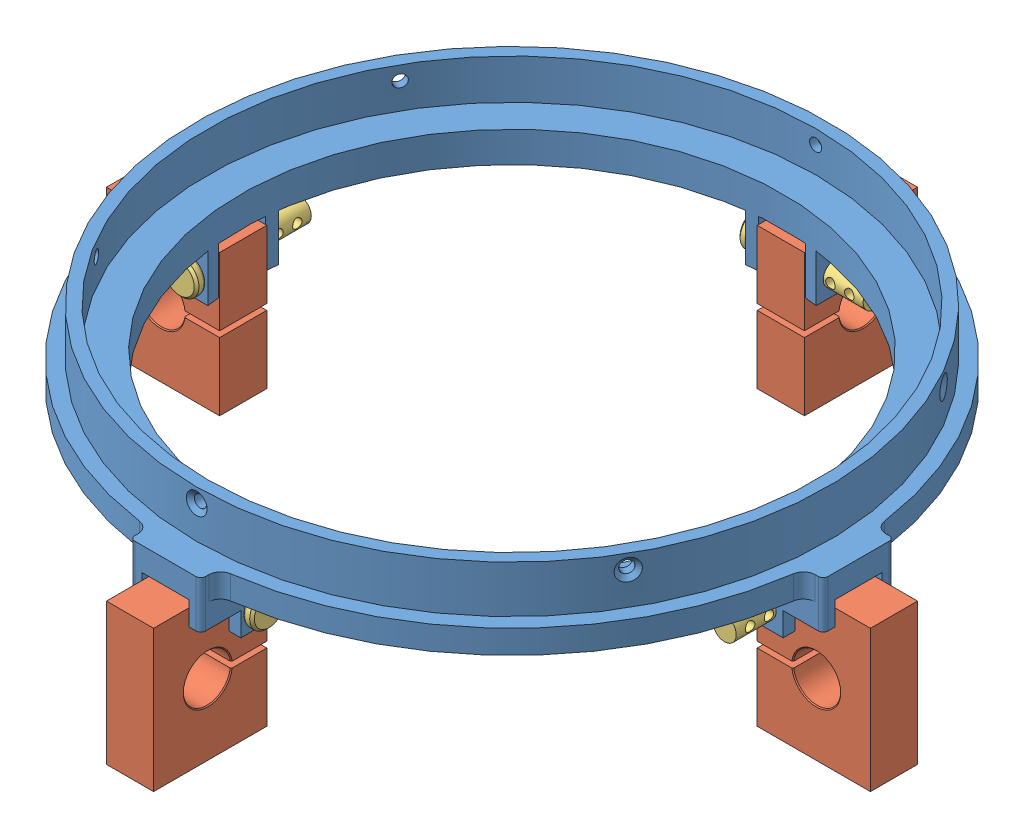
SolidWorks assembly Load cell and motor mount assembly final, configuration Default. Lengths in mm.
Overall size (205.76 59.05 205.76).
9 component instances, 3 part files, 8 mates.
Components (placement in the parent):
- Engine and Load Cell Mounting Plate3-1: Engine and Load Cell Mounting Plate3 [Default] at origin size (186.69 31.75 186.69)
- Load Cell7-4: Load Cell7 [Default] at (0 -20.955 87.6411) x (0 0 -1) z (1 0 0) size (30.48 38.1 12.7)
- load cell pin-2: load cell pin [Default] at (12.065 -7.62 77.4811) x (0 1 0) z (0 0 1) size (9.21 32.32 9.21)
- load cell pin-5: load cell pin [Default] at (77.4811 -7.62 -12.065) x (0 1 0) z (1 0 0) size (9.21 32.32 9.21)
- load cell pin-6: load cell pin [Default] at (-12.065 -7.62 -77.4811) x (0 1 0) z (0 0 -1) size (9.21 32.32 9.21)
- load cell pin-7: load cell pin [Default] at (-77.4811 -7.62 12.065) x (0 1 0) z (-1 0 0) size (9.21 32.32 9.21)
- Load Cell7-5: Load Cell7 [Default] at (87.6411 -20.955 0) x (-1 0 0) z (0 0 -1) size (30.48 38.1 12.7)
- Load Cell7-6: Load Cell7 [Default] at (0 -20.955 -87.6411) x (0 0 1) z (-1 0 0) size (30.48 38.1 12.7)
- Load Cell7-7: Load Cell7 [Default] at (-87.6411 -20.955 0) size (30.48 38.1 12.7)
Mates (geometry in assembly coordinates):
- Coincident1: coincident: plane of Engine and Load Cell Mounting Plate3-1 through (0 0 0) normal (0 0 1); plane of assembly through (0 0 0) normal (0 0 1)
- Coincident2: coincident: plane of Engine and Load Cell Mounting Plate3-1 through (0 0 0) normal (1 0 0); plane of assembly through (0 0 0) normal (1 0 0)
- Coincident3: coincident: plane of Engine and Load Cell Mounting Plate3-1 through (0 0 0) normal (0 1 0); plane of assembly through (0 0 0) normal (0 1 0)
- Concentric1: concentric: circle of load cell pin-2; circle of Engine and Load Cell Mounting Plate3-1
- Concentric2: concentric: circle of Load Cell7-4; circle of Engine and Load Cell Mounting Plate3-1
- Coincident4: coincident: plane of Engine and Load Cell Mounting Plate3-1 through (6.35 -12.7 72.7484) normal (-1 0 0); plane of Load Cell7-4 through (6.35 -20.955 87.6411) normal (1 0 0)
- Coincident5: coincident: plane of Engine and Load Cell Mounting Plate3-1 through (9.525 -12.7 0) normal (1 0 0); plane of load cell pin-2 through (9.525 -7.62 77.4811) normal (-1 0 0)
- Parallel1: parallel: plane of Engine and Load Cell Mounting Plate3-1 through (0 0 0) normal (0 -1 0); plane of Load Cell7-4 through (6.35 -1.905 102.8811) normal (0 1 0)
